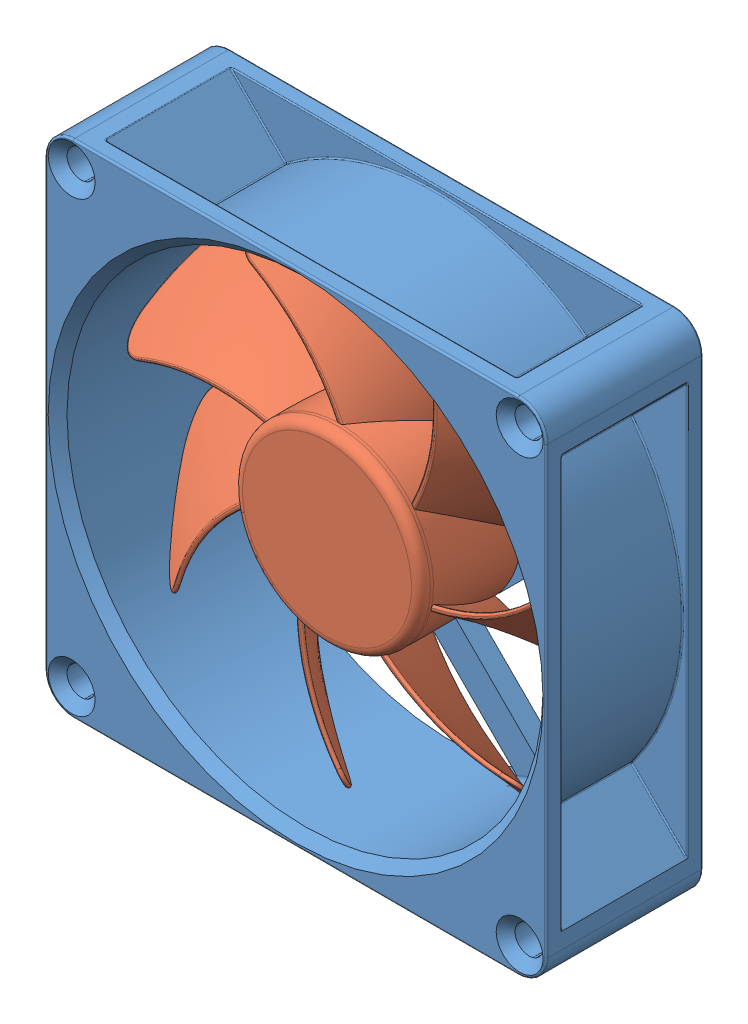
SolidWorks assembly sunon_fan_red, configuration Default. Lengths in mm.
Overall size (85.36 85.78 25.01).
2 component instances, 2 part files, 0 mates.
Components (placement in the parent):
- sunon_frame-1: sunon_frame [Default] at (-24.6386 40.5843 -26.7065) size (80.17 80.17 25.01)
- sunon_blade_80-1: sunon_blade_80 [Default] at (-24.6386 40.5843 -35.2065) x (-0.16104 -0.986948 0) z (0 0 1) size (74.8 74.28 16.09)
